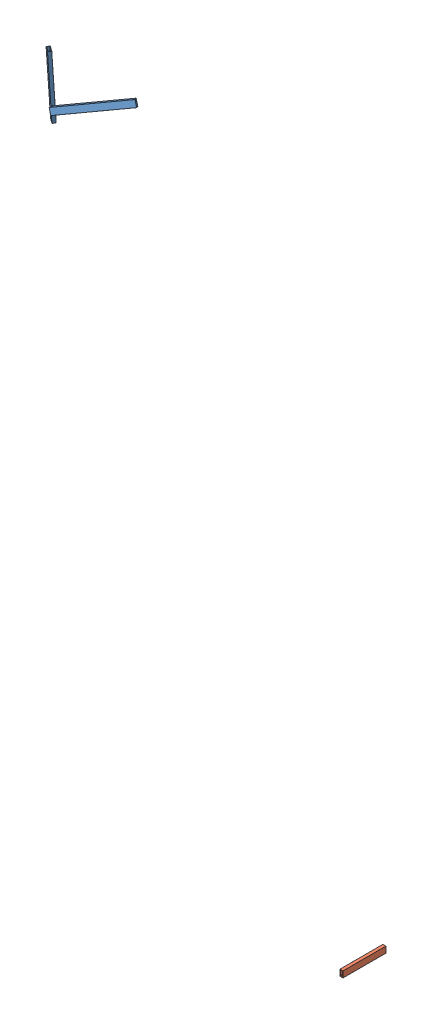
SolidWorks assembly Assem1, configuration Default. Lengths in mm.
Overall size (3916.98 3991.11 1712.11).
3 component instances, 2 part files, 0 mates.
Components (placement in the parent):
- cut 21in extrusion-1: cut 21in extrusion [Default] at (-220.2293 -23.2251 390.4533) x (0.454932 0.254116 0.8535) z (0.81824 0.258969 -0.513242) size (25.4 50.8 533.4)
- cut 21in extrusion-2: cut 21in extrusion [Default] at (-235.4679 -170.0269 362.1566) x (0.584388 0.056091 -0.809533) z (-0.000165 0.997616 0.069004) size (25.4 50.8 533.4)
- box extrusion 14in-1: box extrusion 14in [Default] at (3614.7998 -3625.5382 0) size (25.4 50.8 355.6)
